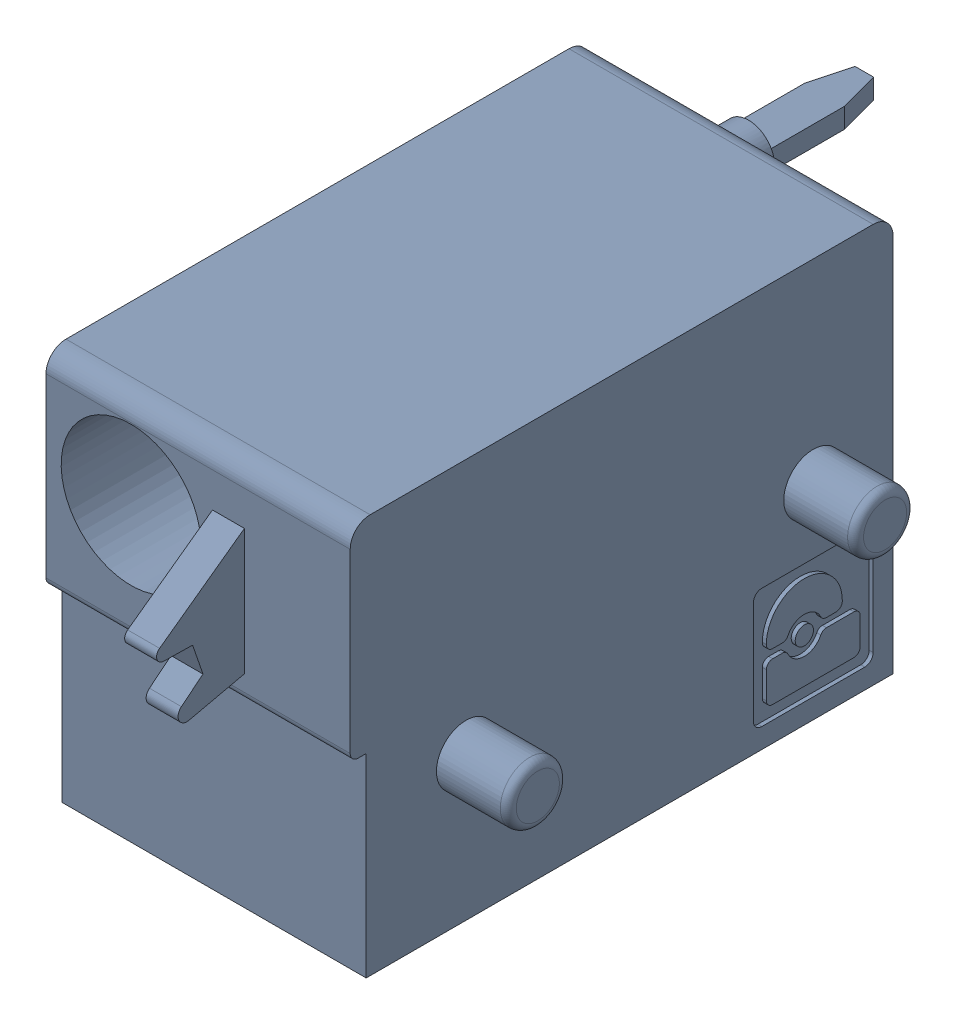
SolidWorks assembly J68, configuration Default. Lengths in mm.
Overall size (9.42 10 19.2).
2 component instances, 1 part files, 0 mates.
Components (placement in the parent):
- 1790377-1: 1790377 [Default] at (194.945 -7.6199 0) x (0 1 0) z (1 0 0) size (10 19.2 9.42)
  - ffkdsa-v2-7.62-1: ffkdsa-v2-7.62 [Default] at (-23.7414 -38.158 -5.08) x (0 -1 0) z (0 0 1) size (19.2 10 9.42)
